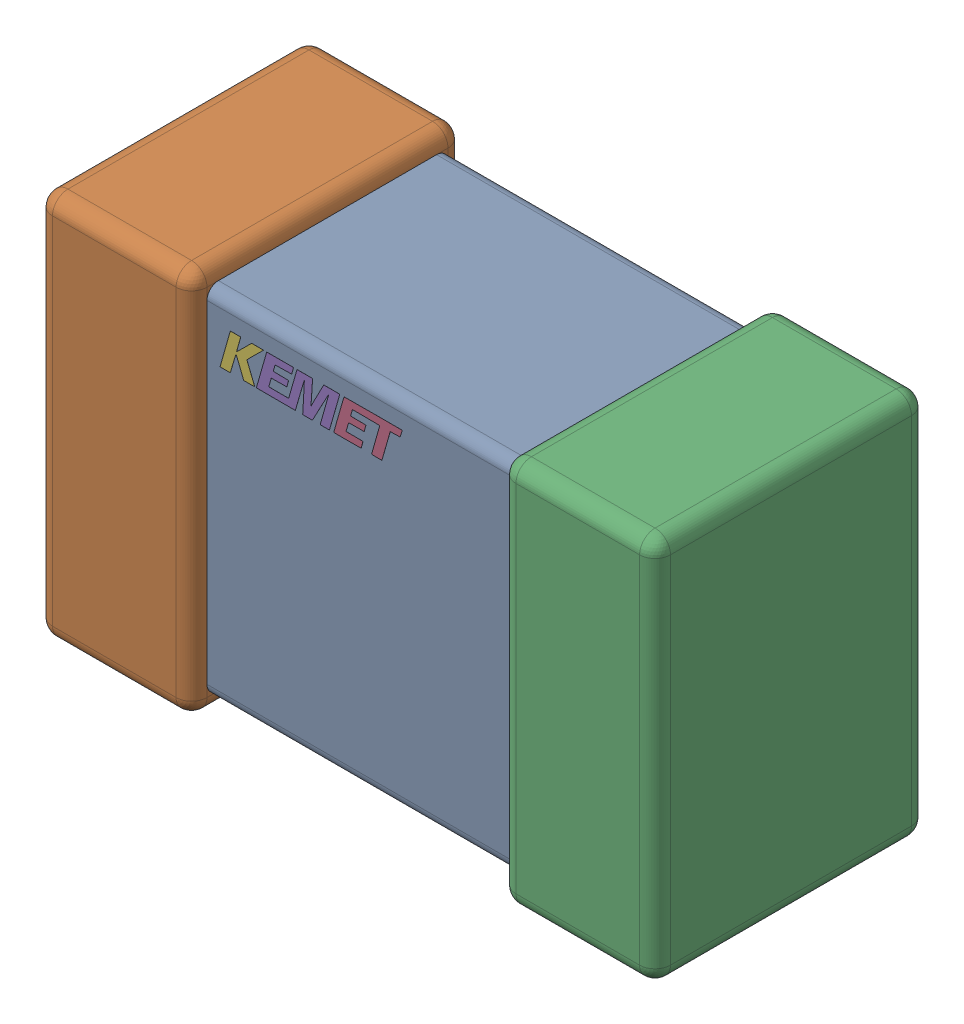
SolidWorks assembly C13.step, configuration Default. Lengths in mm.
Overall size (2 1.25 0.88).
3 component instances, 3 part files, 0 mates.
Components (placement in the parent):
- Cap_KEMET_C0805C472J3HAC_eec.step-1: Cap_KEMET_C0805C472J3HAC_eec.step [Default] at (57.277 8.382 0) size (1 1.15 0.78)
- Cap_KEMET_C0805C472J3HAC_eec-7.step-1: Cap_KEMET_C0805C472J3HAC_eec-7.step [Default] at (57.277 8.382 0) size (2 1.25 0.88)
- Cap_KEMET_C0805C472J3HAC_eec-8.step-1: Cap_KEMET_C0805C472J3HAC_eec-8.step [Default] at (57.277 8.382 0) size (0.59 0.12 0)
